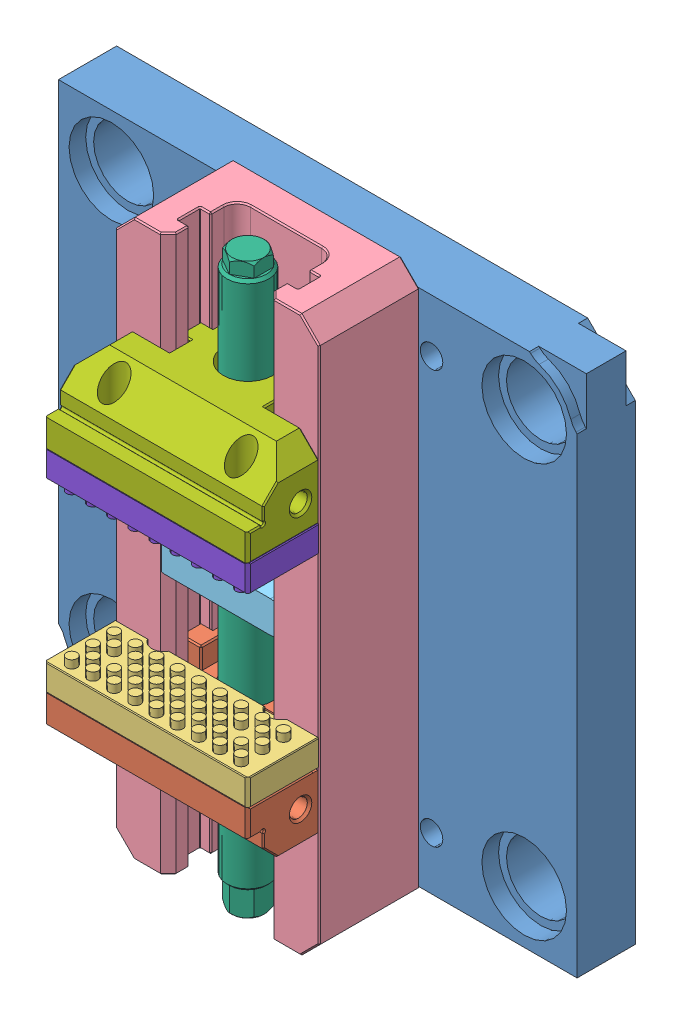
SolidWorks assembly ETAU VARIO 77x95 LONG, configuration Défaut. Lengths in mm.
Overall size (196 215 86.94).
8 component instances, 8 part files, 13 mates.
Components (placement in the parent):
- Copie de F_50_196_196_22_1;Import_e1^ETAU VARIO 77x95 LONG-1: Copie de F_50_196_196_22_1;Import_e1^ETAU VARIO 77x95 LONG [Défaut] at origin size (196 196 22) (virtual)
- Copie de 42077-1101;Import_e1^ETAU VARIO 77x95 LONG-1: Copie de 42077-1101;Import_e1^ETAU VARIO 77x95 LONG [Défaut] at (0 -5 0.14) size (77 37.5 51) (virtual)
- Copie de 42077-1101;Import_e2^ETAU VARIO 77x95 LONG-1: Copie de 42077-1101;Import_e2^ETAU VARIO 77x95 LONG [Défaut] at (0 -5 0.14) size (77 13 32) (virtual)
- Copie de 47200;Import_e1^ETAU VARIO 77x95 LONG-1: Copie de 47200;Import_e1^ETAU VARIO 77x95 LONG [Défaut] at origin size (77 210 38) (virtual)
- Copie de 47200;Import_e2^ETAU VARIO 77x95 LONG-1: Copie de 47200;Import_e2^ETAU VARIO 77x95 LONG [Défaut] at origin size (48.8 12 25.8) (virtual)
- Copie de 47200;Import_e3^ETAU VARIO 77x95 LONG-1: Copie de 47200;Import_e3^ETAU VARIO 77x95 LONG [Défaut] at origin size (16 215 16) (virtual)
- Copie de 42077-1101;Import_e1-1^ETAU VARIO 77x95 LONG-1: Copie de 42077-1101;Import_e1-1^ETAU VARIO 77x95 LONG [Défaut] at (0 5 0.14) size (77 37.5 51) (virtual)
- Copie de 42077-1101;Import_e2-1^ETAU VARIO 77x95 LONG-1: Copie de 42077-1101;Import_e2-1^ETAU VARIO 77x95 LONG [Défaut] at (0 5 0.14) size (77 13 32) (virtual)
Mates (geometry in assembly coordinates):
- Verrouiller2: lock: unknown of Copie de 42077-1101;Import_e1^ETAU VARIO 77x95 LONG-1; unknown of Copie de 42077-1101;Import_e2^ETAU VARIO 77x95 LONG-1
- Verrouiller3: lock: unknown of Copie de 42077-1101;Import_e1^ETAU VARIO 77x95 LONG-1; unknown of Copie de 42077-1101;Import_e2^ETAU VARIO 77x95 LONG-1
- Verrouiller4: lock: unknown of Copie de 42077-1101;Import_e1-1^ETAU VARIO 77x95 LONG-1; unknown of Copie de 42077-1101;Import_e2-1^ETAU VARIO 77x95 LONG-1
- Verrouiller5: lock: unknown of Copie de F_50_196_196_22_1;Import_e1^ETAU VARIO 77x95 LONG-1; unknown of Copie de 47200;Import_e1^ETAU VARIO 77x95 LONG-1
- Verrouiller6: lock: unknown of Copie de 47200;Import_e2^ETAU VARIO 77x95 LONG-1; unknown of Copie de 47200;Import_e3^ETAU VARIO 77x95 LONG-1
- Verrouiller7: lock: unknown of Copie de 47200;Import_e1^ETAU VARIO 77x95 LONG-1; unknown of Copie de 47200;Import_e2^ETAU VARIO 77x95 LONG-1
- Coïncidente1: coincident: plane of Copie de 42077-1101;Import_e2^ETAU VARIO 77x95 LONG-1 through (73 -5 0.14) normal (1 0 0); plane of Copie de 47200;Import_e1^ETAU VARIO 77x95 LONG-1 through (73 0 0) normal (1 0 0)
- Coïncidente2: coincident: plane of Copie de 47200;Import_e1^ETAU VARIO 77x95 LONG-1 through (73 0 0) normal (1 0 0); plane of Copie de 42077-1101;Import_e2-1^ETAU VARIO 77x95 LONG-1 through (73 5 0.14) normal (1 0 0)
- Coïncidente3: coincident: plane of Copie de 42077-1101;Import_e1^ETAU VARIO 77x95 LONG-1 through (111.5 -43.1233 136) normal (0 0 -1); plane of Copie de 47200;Import_e1^ETAU VARIO 77x95 LONG-1 through (111.5 129.8767 136) normal (0 0 1)
- Coïncidente4: coincident: plane of Copie de 47200;Import_e1^ETAU VARIO 77x95 LONG-1 through (111.5 129.8767 136) normal (0 0 1); plane of Copie de 42077-1101;Import_e1-1^ETAU VARIO 77x95 LONG-1 through (111.5 92.8767 136) normal (0 0 -1)
- Coïncidente5: coincident: plane of Copie de 47200;Import_e1^ETAU VARIO 77x95 LONG-1 through (0 24.8767 0) normal (0 -1 0); plane of assembly through (0 24.8767 0) normal (0 -1 0)
- Distance1: distance = 60 mm: plane of Copie de 42077-1101;Import_e2^ETAU VARIO 77x95 LONG-1 through (34.5 -5.1233 162.94) normal (0 1 0); plane of Copie de 42077-1101;Import_e2-1^ETAU VARIO 77x95 LONG-1 through (111.5 54.8767 162.94) normal (0 -1 0)
- Symétrique1: symmetric: plane of Copie de 42077-1101;Import_e2^ETAU VARIO 77x95 LONG-1 through (34.5 -5.1233 162.94) normal (0 1 0); plane of Copie de 42077-1101;Import_e2-1^ETAU VARIO 77x95 LONG-1 through (111.5 54.8767 162.94) normal (0 -1 0); plane of Copie de 47200;Import_e1^ETAU VARIO 77x95 LONG-1 through (0 24.8767 0) normal (0 -1 0)
